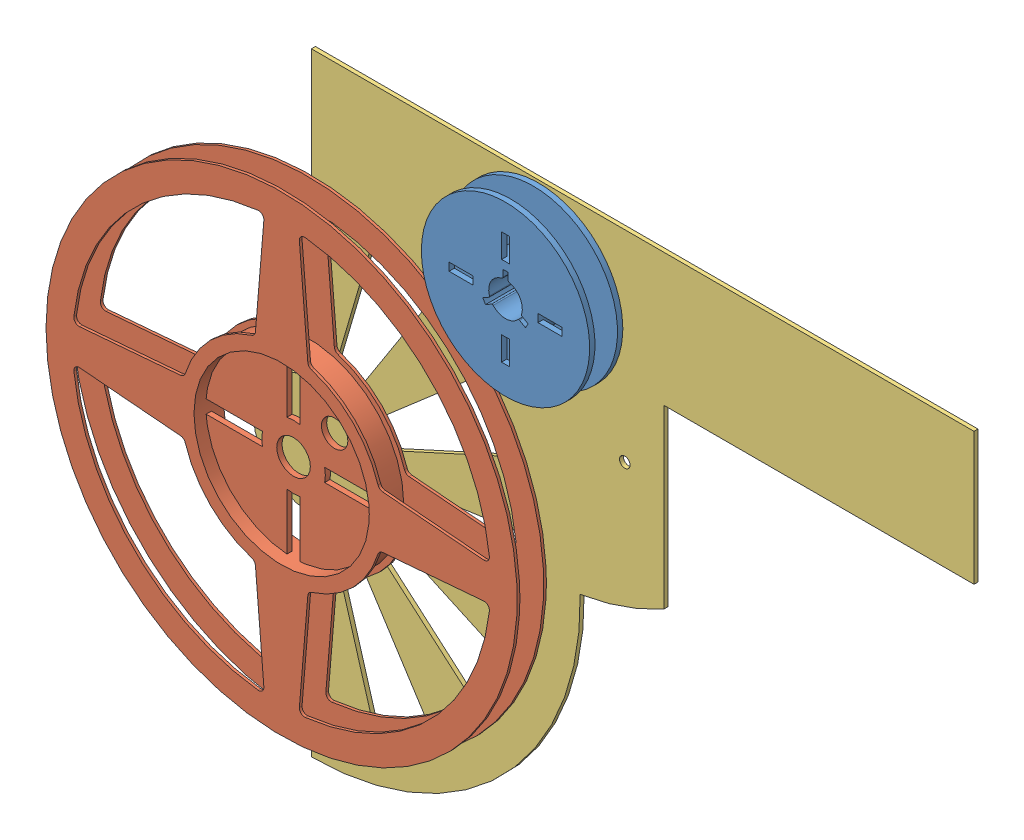
SolidWorks assembly Open Feeder, configuration Default. Lengths in mm.
Overall size (338.9 231.43 14.25).
3 component instances, 3 part files, 4 mates.
Components (placement in the parent):
- 8mm cover stripper-1: 8mm cover stripper [Default] at (-26.778 22.0757 -7.1175) size (63.5 63.5 12.5)
- 8mm Reel-1: 8mm Reel [Default] at (-112.755 -75.4331 2.8825) size (177.8 177.8 11)
- mounting plate-1: mounting plate [Default] at (-112.755 -75.4331 -8.8675) size (272 231.43 1.5)
Mates (geometry in assembly coordinates):
- Coincident1: coincident aligned: plane of 8mm cover stripper-1 through (-26.778 22.0757 -7.1175) normal (0 0 -1); plane of 8mm Reel-1 through (-118.4735 -69.3432 -7.1175) normal (0 0 -1)
- Distance1: distance = 0.25 mm anti-aligned: plane of mounting plate-1 through (-26.778 22.0757 -7.3675) normal (0 0 1); plane of 8mm Reel-1 through (-112.755 -75.4331 -7.1175) normal (0 0 -1)
- Concentric1: concentric anti-aligned: circle of 8mm Reel-1; circle of mounting plate-1
- Concentric2: concentric anti-aligned: cylinder of 8mm cover stripper-1 through (-26.778 22.0757 5.3825) axis (0 0 -1) radius 6.35; circle of mounting plate-1
